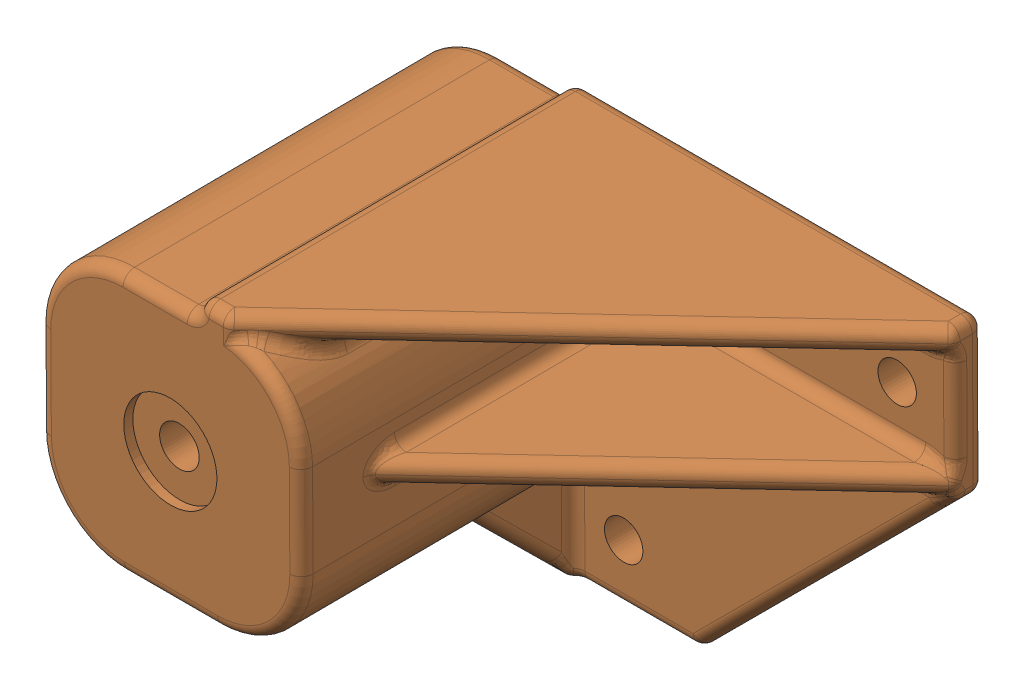
SolidWorks assembly MirrorM2 Y AXIS TENSIONER, configuration Default. Lengths in mm.
Overall size (97.52 70.4 65.59).
8 component instances, 6 part files, 10 mates.
Components (placement in the parent):
- Mirror3684N13_Corrosion-Resistant HTD Timing Belt Pulley-1: Mirror3684N13_Corrosion-Resistant HTD Timing Belt Pulley [3684N13] at (22 11.8814 -55.6654) x (0 -0.999705 0.02427) z (1 0 0) size (18 18 18)
- MirrorM2 Tensioner Core-1: MirrorM2 Tensioner Core [Default] at (20 11.9553 -67.6652) x (0 0.999981 0.006159) z (0 0.006159 -0.999981) size (35 35 45)
- Mirror6153K69_Stainless Steel Ball Bearing-1: Mirror6153K69_Stainless Steel Ball Bearing [6153K69] at (33.5 11.8814 -55.6654) x (0 0 1) z (-1 0 0) size (16 16 5)
- Mirror6153K69_Stainless Steel Ball Bearing-2: Mirror6153K69_Stainless Steel Ball Bearing [6153K69] at (6.5 11.8814 -55.6654) x (0 -0.030525 -0.999534) z (1 0 0) size (16 16 5)
- Mirror2mm spacer-1: Mirror2mm spacer [Default] at (29 11.8814 -55.6654) x (0 -1 0) z (0 0 1) size (9.5 2 9.5)
- Mirror2mm spacer-2: Mirror2mm spacer [Default] at (11 11.8814 -55.6654) x (0 1 0) z (0 0 1) size (9.5 2 9.5)
- MirrorM2 Tensioner Shell-1: MirrorM2 Tensioner Shell [Default] at (20 11.9758 -70.9978) x (-1 0 0) z (0 0.006159 -0.999981) size (97.52 70 65.16)
- MirrorY Tensioner Shaft-1: MirrorY Tensioner Shaft [Default] at (2.5 11.8814 -55.6654) x (0 0.381849 0.924225) z (0 0.924225 -0.381849) size (5 35 5)
Mates (geometry in assembly coordinates):
- Concentric1: concentric aligned: cylinder of MirrorM2 Tensioner Core-1 through (2.5 11.8814 -55.6654) axis (1 0 0) radius 3.5; circle of Mirror6153K69_Stainless Steel Ball Bearing-2
- Concentric2: concentric aligned: cylinder of MirrorM2 Tensioner Core-1 through (2.5 11.8814 -55.6654) axis (1 0 0) radius 3.5; cylinder of Mirror6153K69_Stainless Steel Ball Bearing-1 through (36 11.8814 -55.6654) axis (1 0 0) radius 2.5
- Coincident1: coincident anti-aligned: plane of Mirror6153K69_Stainless Steel Ball Bearing-1 through (31 14.6314 -55.6654) normal (-1 0 0); plane of Mirror2mm spacer-1 through (31 11.8814 -55.6654) normal (1 0 0)
- Concentric3: concentric anti-aligned: cylinder of Mirror6153K69_Stainless Steel Ball Bearing-1 through (36 11.8814 -55.6654) axis (1 0 0) radius 2.5; circle of Mirror2mm spacer-1
- Coincident2: coincident anti-aligned: plane of Mirror6153K69_Stainless Steel Ball Bearing-2 through (9 14.6301 -55.7493) normal (1 0 0); plane of Mirror2mm spacer-2 through (9 11.8814 -55.6654) normal (-1 0 0)
- Concentric4: concentric anti-aligned: cylinder of Mirror6153K69_Stainless Steel Ball Bearing-2 through (4 11.8814 -55.6654) axis (-1 0 0) radius 2.5; cylinder of Mirror2mm spacer-2 through (9 11.8814 -55.6654) axis (1 0 0) radius 2.6
- Distance1: distance = 0.5 mm anti-aligned: plane of MirrorM2 Tensioner Core-1 through (37.5 -5.7291 -37.7735) normal (1 0 0); plane of MirrorM2 Tensioner Shell-1 through (38 11.5755 -5.999) normal (-1 0 0)
- Distance2: distance = 0.5 mm anti-aligned: plane of MirrorM2 Tensioner Shell-1 through (20 29.5752 -5.8881) normal (0 -0.999981 -0.006159); plane of MirrorM2 Tensioner Core-1 through (37.5 29.2702 -37.558) normal (0 0.999981 0.006159)
- Coincident3: coincident aligned: plane of MirrorM2 Tensioner Core-1 through (37.5 -5.7291 -37.7735) normal (1 0 0); plane of MirrorY Tensioner Shaft-1 through (37.5 11.8814 -55.6654) normal (1 0 0)
- Concentric5: concentric anti-aligned: cylinder of MirrorM2 Tensioner Core-1 through (2.5 11.8814 -55.6654) axis (1 0 0) radius 3.5; cylinder of MirrorY Tensioner Shaft-1 through (37.5 11.8814 -55.6654) axis (-1 0 0) radius 2.5
